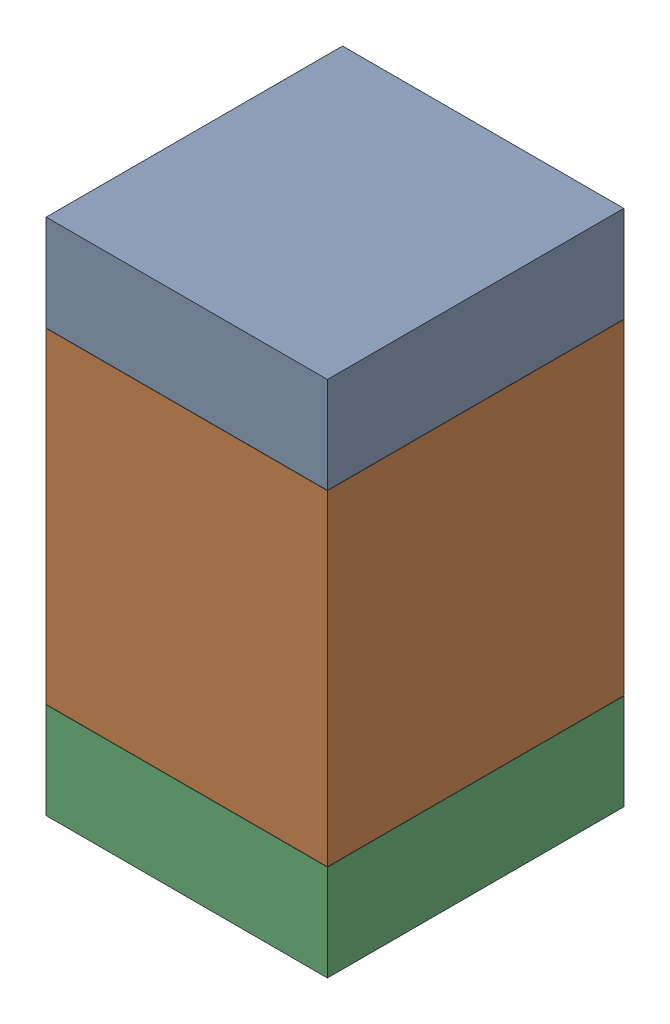
SolidWorks assembly R26, configuration Default. Lengths in mm.
Overall size (0.95 1.75 1).
6 component instances, 2 part files, 0 mates.
Components (placement in the parent):
- 6575495072-1: 6575495072 [Default] at (38.354 16.5875 0) size (0.95 0.32 1)
  - Extruded_6-1: Extruded_6 [Default] at origin size (0.95 0.32 1)
- 6575494912-1: 6575494912 [Default] at (38.354 15.875 0) size (0.95 1.1 1)
  - Extruded_7-1: Extruded_7 [Default] at origin size (0.95 1.1 1)
- 6575495072-2: 6575495072 [Default] at (38.354 15.1625 0) size (0.95 0.32 1)
  - Extruded_6-1: Extruded_6 [Default] at origin size (0.95 0.32 1)
